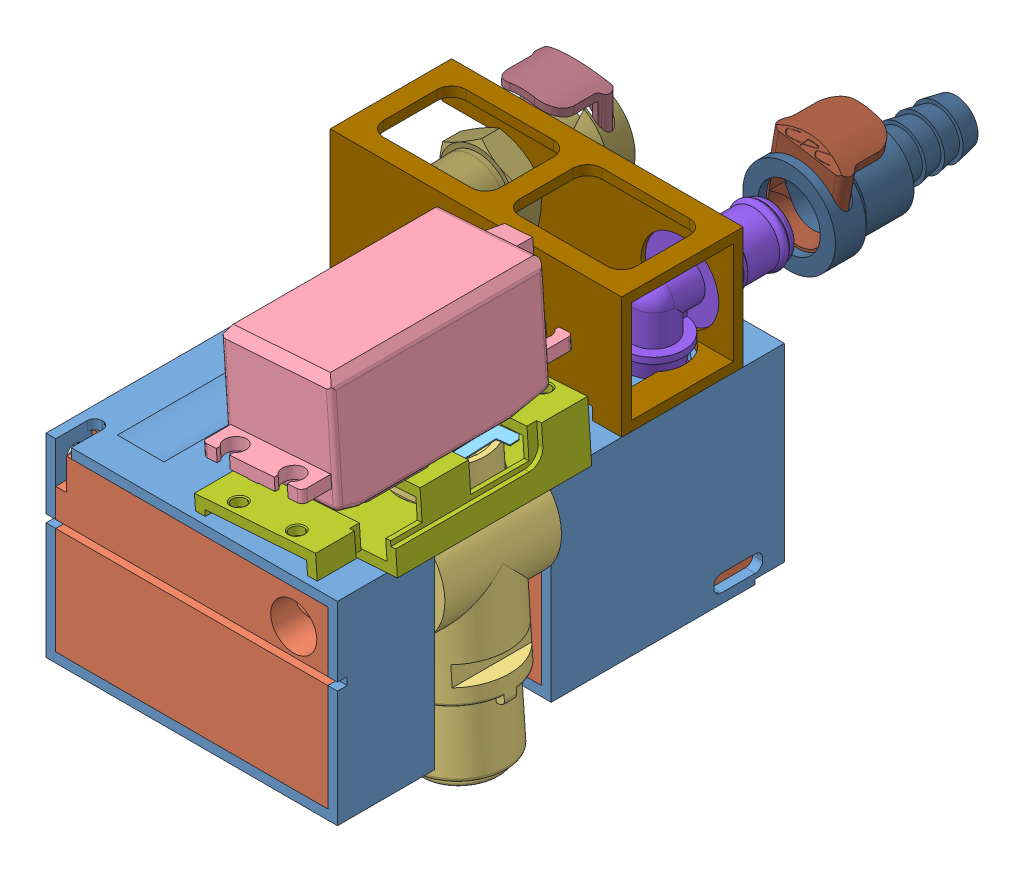
SolidWorks assembly Пневмо5, configuration По умолчанию. Lengths in mm.
Overall size (64.76 87.35 144.77).
16 component instances, 14 part files, 28 mates.
Components (placement in the parent):
- оболочка5-1: оболочка5 [По умолчанию] at (-105.9594 11.2574 -50) size (60 40 92)
- камера_фильтра_v5-1: камера_фильтра_v5 [По умолчанию] at (-133.9594 29.2574 -50) x (-1 0 0) z (0 0 1) size (56 36 92)
- 326-6SMC6SMC6SMC-B_NO_NUT-1: 326-6SMC6SMC6SMC-B_NO_NUT [По умолчанию] at (-84.9594 22.2574 -23.401) x (0 0 1) z (-0.069756 0.997564 0) size (24 22.23 55.93)
- HS-75bb_real-1: HS-75bb_real [По умолчанию] at (-86.5691 45.2779 10) x (-0.997564 -0.069756 0) z (0 0 1) size (22.86 27.85 55.91)
- стрелка-1: стрелка [По умолчанию] at (-86.2778 40.2861 8.7513) x (-0.045952 -0.003213 -0.998938) z (0.996505 0.069682 -0.046064) size (10 0.2 20.5)
- муфта_HS311-1: муфта_HS311 [По умолчанию] at (-86.5343 44.7792 10) x (-0.045952 -0.003213 -0.998938) z (0.069756 -0.997564 0) size (10 10 6.4)
- мостик_v5-1-1: мостик_v5-1 [По умолчанию] at (-86.0057 37.2208 -7.5) x (-0.997564 -0.069756 0) z (0 0 1) size (25 12 56)
- APC23006-1: APC23006 [По умолчанию] at (-86.9594 42.2344 -58.13) x (-1 0 0) z (0 0 -1) size (16 32.26 30.48)
- угольник_APC23006-1: угольник_APC23006 [Default] at (-75.9594 31.2574 -41.5) x (-1 0 0) z (0 0 -1) size (60 25 25)
- планка_2хМ3-1: планка_2хМ3 [По умолчанию] at (-131.9594 29.7574 44) x (-1 0 0) z (0 0 -1) (suppressed, hidden)
- apc17006_6_0-1: apc17006_6_0 [По умолчанию] at (-86.9594 42.2344 -61.9745) x (0.98631 -0.164903 0) z (0 0 1) size (19.05 23.5 34.3)
  - APC17006-BODY-1: APC17006-BODY [По умолчанию] at origin size (19.05 19.05 34.3)
  - APC-LATCH-1: APC-LATCH [По умолчанию] at origin size (15.11 23.5 12.49)
- apc10004_6_0-1: apc10004_6_0 [По умолчанию] at (-123.4594 42.2574 -57.2665) x (-0.999958 0.0092 0) z (0 0 -1) size (19.05 23.5 35.56)
  - APC10004-BODY-1: APC10004-BODY [По умолчанию] at origin size (19.05 19.05 35.56)
  - APC-LATCH_1-1: APC-LATCH_1 [По умолчанию] at origin size (15.11 23.5 12.49)
Mates (geometry in assembly coordinates):
- Ширина1: width aligned: plane of камера_фильтра_v5-1 through (-133.9594 29.2574 42) normal (-1 0 0); plane of камера_фильтра_v5-1 through (-77.9594 29.2574 42) normal (1 0 0); plane of оболочка5-1 through (-77.9594 -6.7426 42) normal (-1 0 0); plane of оболочка5-1 through (-133.9594 -6.7426 42) normal (1 0 0)
- Ширина2: width aligned: plane of камера_фильтра_v5-1 through (-77.9594 29.2574 42) normal (0 1 0); plane of камера_фильтра_v5-1 through (-77.9594 -6.7426 42) normal (0 -1 0); plane of оболочка5-1 through (-133.9594 -6.7426 42) normal (0 1 0); plane of оболочка5-1 through (-133.9594 29.2574 42) normal (0 -1 0)
- Совпадение1: coincident aligned: plane of оболочка5-1 through (-75.9594 31.2574 -50) normal (0 0 -1); plane of камера_фильтра_v5-1 through (-133.9594 -6.7426 -50) normal (0 0 -1)
- Концентричный1: concentric anti-aligned: cylinder of камера_фильтра_v5-1 through (-84.9594 22.2574 -39.435) axis (0 0 1) radius 4.75; cylinder of 326-6SMC6SMC6SMC-B_NO_NUT-1 through (-84.9594 22.2574 -23.401) axis (0 0 -1) radius 7
- Ширина3: width anti-aligned: plane of 326-6SMC6SMC6SMC-B_NO_NUT-1 through (-85.4477 29.2403 22) normal (0 0 1); plane of 326-6SMC6SMC6SMC-B_NO_NUT-1 through (-85.4477 29.2403 -2) normal (0 0 -1); plane of камера_фильтра_v5-1 through (-101.9594 29.2574 22) normal (0 0 -1); plane of камера_фильтра_v5-1 through (-77.9594 29.2574 -2) normal (0 0 1)
- Расстояние1: distance = 0.2 mm anti-aligned: plane of муфта_HS311-1 through (-86.5343 44.7792 10) normal (-0.069756 0.997564 0); plane of HS-75bb_real-1 through (-92.0248 44.5957 10) normal (0.069756 -0.997564 0)
- Параллельность1: parallel anti-aligned: plane of HS-75bb_real-1 through (-76.8795 70.5655 48.481) normal (0.997564 0.069756 0); plane of мостик_v5-1-1 through (-98.8938 42.3342 48.5) normal (-0.997564 -0.069756 0)
- Концентричный3: concentric aligned: cylinder of 326-6SMC6SMC6SMC-B_NO_NUT-1 through (-86.9438 50.6361 10) axis (0.069756 -0.997564 0) radius 7.5; cylinder of HS-75bb_real-1 through (-86.5901 45.5772 10) axis (0.069756 -0.997564 0) radius 7
- Концентричный4: concentric aligned: cylinder of HS-75bb_real-1 through (-86.3057 41.5103 10) axis (-0.069756 0.997564 0) radius 2.88; cylinder of муфта_HS311-1 through (-86.332 41.8862 10) axis (-0.069756 0.997564 0) radius 4.55
- Ширина6: width anti-aligned: plane of стрелка-1 through (-93.5358 39.9791 14.0915) normal (0.045952 0.003213 0.998938); plane of стрелка-1 through (-81.4241 40.826 6.0237) normal (-0.045952 -0.003213 -0.998938); plane of муфта_HS311-1 through (-85.9155 38.4068 13.746) normal (-0.045952 -0.003213 -0.998938); plane of муфта_HS311-1 through (-86.2601 38.3827 6.254) normal (0.045952 0.003213 0.998938)
- Ширина7: width aligned: plane of стрелка-1 through (-91.3892 40.1292 6.4843) normal (0.996505 0.069682 -0.046064); plane of стрелка-1 through (-81.539 40.818 3.5263) normal (-0.996505 -0.069682 0.046064); plane of муфта_HS311-1 through (-81.2518 40.838 9.7697) normal (0.996505 0.069682 -0.046064); plane of муфта_HS311-1 through (-91.2168 40.1412 10.2303) normal (-0.996505 -0.069682 0.046064)
- Совпадение6: coincident anti-aligned: plane of стрелка-1 through (-96.7357 39.7553 4.2288) normal (-0.069756 0.997564 0); plane of муфта_HS311-1 through (-97.3368 39.7133 10.5132) normal (0.069756 -0.997564 0)
- Совпадение8: coincident anti-aligned: plane of 326-6SMC6SMC6SMC-B_NO_NUT-1 through (-85.5872 31.2354 1) normal (-0.069756 0.997564 0); plane of мостик_v5-1-1 through (-73.1177 32.1074 48.5) normal (0.069756 -0.997564 0)
- Концентричный5: concentric aligned: cylinder of 326-6SMC6SMC6SMC-B_NO_NUT-1 through (-85.5724 31.0243 10) axis (0.069756 -0.997564 0) radius 8.7312; cylinder of мостик_v5-1-1 through (-86.4243 43.2072 10) axis (0.069756 -0.997564 0) radius 9
- Параллельность2: parallel: plane of оболочка5-1 through (-75.9594 -8.7426 42) normal (1 0 0); line of мостик_v5-1-1 through (-98.8938 42.3342 48.5) axis (0 0 -1)
- Параллельность3: parallel anti-aligned: plane of оболочка5-1 through (-135.9594 31.2574 42) normal (0 1 0); plane of мостик_v5-1-1 through (-98.0568 31.2782 21.5) normal (0 -1 0)
- Концентричный57: concentric aligned: cylinder of оболочка5-1 through (-86.9594 -8.7436 -34) axis (0 1 0) radius 5.5; cylinder of APC23006-1 through (-86.9594 35.1224 -34) axis (0 1 0) radius 6.35
- Параллельность59: parallel aligned: plane of оболочка5-1 through (-75.9594 31.2574 -50) normal (0 0 -1); plane of APC23006-1 through (-86.9594 49.4099 -41.62) normal (0 0 -1)
- Расстояние198: distance = 4.5 mm aligned: plane of APC23006-1 through (-86.9594 35.7574 -28.666) normal (0 1 0); plane of оболочка5-1 through (-135.9594 31.2574 42) normal (0 1 0)
- Совпадение9: coincident anti-aligned: plane of оболочка5-1 through (-135.9594 31.2574 42) normal (0 1 0); plane of угольник_APC23006-1 through (-135.9594 31.2574 -1.3586) normal (0 -1 0)
- Параллельность61: parallel aligned: plane of оболочка5-1 through (-75.9594 31.2574 -50) normal (0 0 -1); plane of угольник_APC23006-1 through (-135.9594 43.7574 -41.5) normal (0 0 -1)
- Концентричный58: concentric anti-aligned: cylinder of APC23006-1 through (-86.9594 35.1224 -34) axis (0 1 0) radius 6.35; cylinder of угольник_APC23006-1 through (-86.9594 35.7574 -34) axis (0 -1 0) radius 6.5
- Совпадение10: coincident anti-aligned: plane of оболочка5-1 through (-133.9594 -6.7426 42) normal (1 0 0); plane of планка_2хМ3-1 through (-133.9594 29.7574 60.9682) normal (-1 0 0)
- Концентричный59: concentric aligned: cylinder of оболочка5-1 through (-135.9594 26.7574 38) axis (-1 0 0) radius 1.6; cylinder of планка_2хМ3-1 through (-133.9594 26.7574 38) axis (-1 0 0) radius 1.5
- Параллельность62: parallel anti-aligned: plane of оболочка5-1 through (-75.9594 31.2574 42) normal (0 0 1); plane of планка_2хМ3-1 through (-133.9594 29.7574 35) normal (0 0 -1)
- Концентричный60: concentric anti-aligned: cylinder of apc17006_6_0-1/APC17006-BODY-1 through (-86.9594 42.2344 -64.5399) axis (0 0 1) radius 6.4135; cylinder of APC23006-1 through (-86.9594 42.2344 -42.5725) axis (0 0 -1) radius 6.35
- Расстояние199: distance = 0.2 mm: plane of apc17006_6_0-1/APC17006-BODY-1 through (-86.174 46.9317 -61.9745) normal (0 0 1); plane of APC23006-1 through (-86.9594 49.4099 -41.62) normal (0 0 -1)
- Концентричный61: concentric aligned: cylinder of угольник_APC23006-1 through (-123.4594 42.2574 -16.499) axis (0 0 -1) radius 7.5; cylinder of apc10004_6_0-1/APC10004-BODY-1 through (-123.4594 42.2574 -44.4014) axis (0 0 -1) radius 7.112
